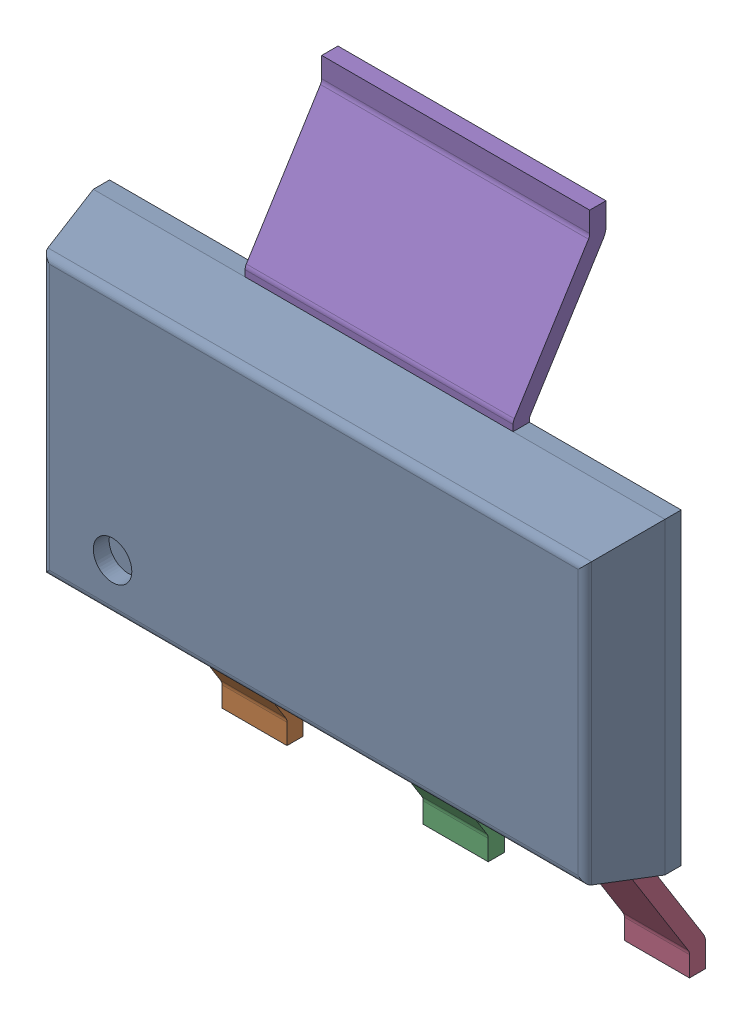
SolidWorks assembly IC10_1.step, configuration Default. Lengths in mm.
Overall size (6.51 7 1.8).
4 component instances, 3 part files, 0 mates.
Components (placement in the parent):
- 6348795088_1.step-11: 6348795088_1.step [Default] at (448.934 292.118 0) x (0 1 0) z (0 0 1) size (7 6.51 1.8)
  - Body-18_1.step-11: Body-18_1.step [Default] at origin size (3.5 6.51 1.06)
  - PinsArrayL_1.step-11: PinsArrayL_1.step [Default] at origin size (1.75 5.32 1.06)
  - FilletPinR_1.step-11: FilletPinR_1.step [Default] at origin size (1.75 3.05 1.06)
